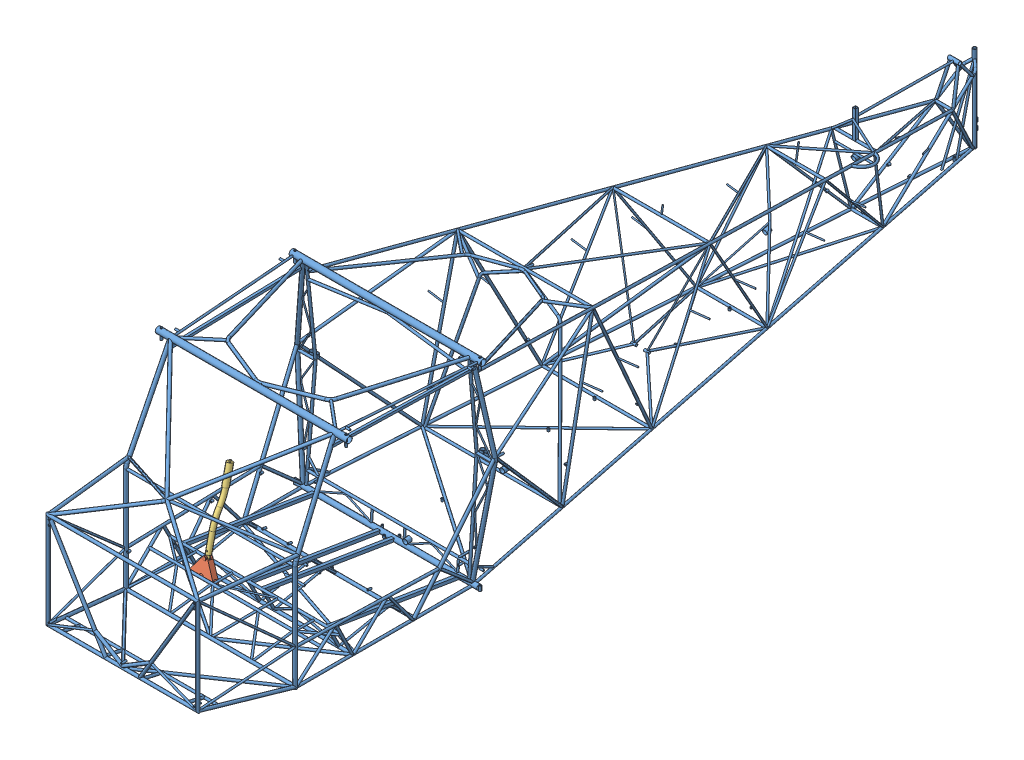
SolidWorks assembly StickFrame Assembly, configuration Default. Lengths in mm.
Overall size (1052.27 1057.27 4469.9).
4 component instances, 4 part files, 5 mates.
Components (placement in the parent):
- Fuselage Tubes rev 3-1: Fuselage Tubes rev 3 [Default<As Machined>] at (1227.5205 2520.4206 5830.4925) size (1052.27 1057.27 4469.9)
- Bottom Triangle-1: Bottom Triangle [Default] at (1008.9455 2084.1475 5181.8887) x (1 0 0) z (0 0.288645 0.957436) size (130 102.5 38)
- Stick-1: Stick [Default] at (1007.1097 2109.0644 5160.7989) x (-0.998126 -0.058587 0.017663) z (0 -0.288645 -0.957436) size (30 452.5 58.21)
- Stick-Triangle Pin-1: Stick-Triangle Pin [Default] at (1008.9455 2075.7768 5154.1231) x (0.999736 -0.022013 0.006636) z (0 0.288645 0.957436) size (9.5 9.5 32)
Mates (geometry in assembly coordinates):
- Distance2: distance = 13 mm: point of Stick-1; plane of Bottom Triangle-1 through (1008.9455 2076.6428 5156.9954) normal (0 0.288645 0.957436)
- Concentric2: concentric aligned: cylinder of Stick-1 through (1008.9455 2084.0032 5181.41) axis (0 -0.288645 -0.957436) radius 3.75; cylinder of Stick-Triangle Pin-1 through (1008.9455 2085.0135 5184.761) axis (0 -0.288645 -0.957436) radius 3.75
- Coincident5: coincident anti-aligned: circle of Bottom Triangle-1; circle of Stick-Triangle Pin-1
- Distance3: distance = 57.3669 mm: cylinder of Bottom Triangle-1 through (943.9455 2008.5874 5191.0904) axis (1 0 0) radius 15; cylinder of Fuselage Tubes rev 3-1 through (783.0205 1929.8706 5078.0175) axis (0.832965 0 0.553326) radius 6.35
- Distance4: distance = 125 mm aligned: plane of Bottom Triangle-1 through (1073.9455 2084.1475 5181.8887) normal (1 0 0); plane of Fuselage Tubes rev 3-1 through (1198.9455 1928.3871 4450.6487) normal (1 0 0)
